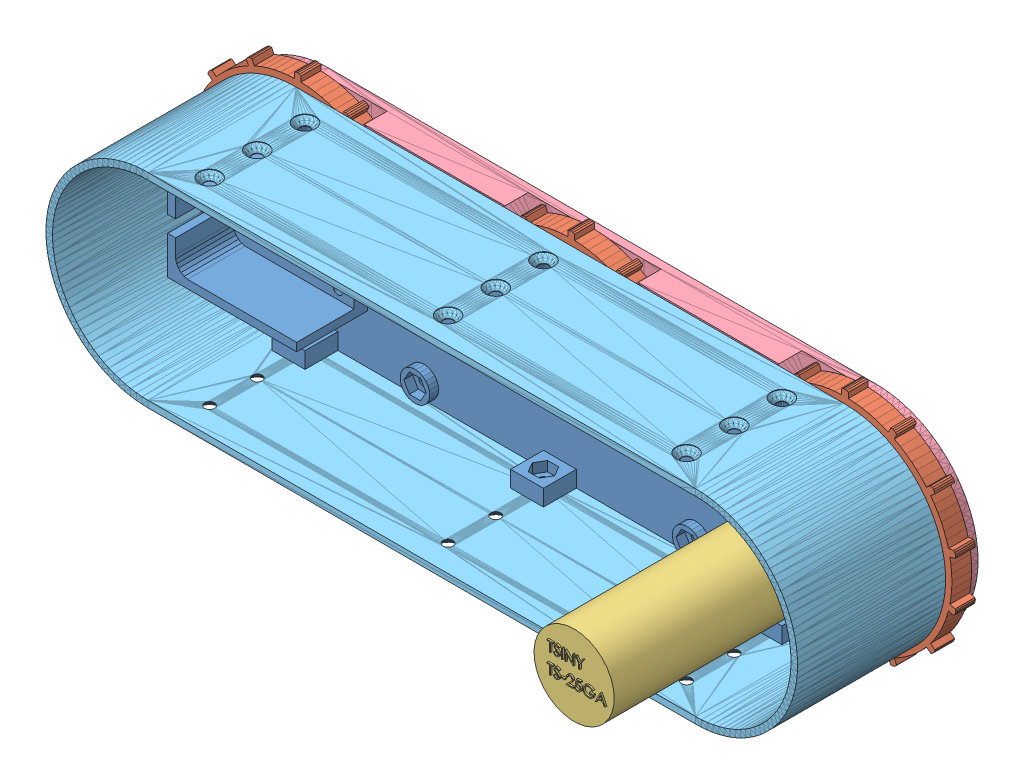
SolidWorks assembly Wheel Assembly with Cover, configuration Default. Lengths in mm.
Overall size (331.86 130.52 98.86).
8 component instances, 6 part files, 0 mates.
Components (placement in the parent):
- Motor_mount_plateV1-1: Motor_mount_plateV1 [Default] at (-100.9316 65.0429 10.2771) size (224.5 58 24.5)
- TrackWheel_V1-1: TrackWheel_V1 [Default] at (-184.1875 65.0685 3.7212) size (67.25 68.9 11)
- TrackWheel_V1-2: TrackWheel_V1 [Default] at (-100.9384 65.0603 3.8007) size (67.25 68.9 11)
- TrackWheel_V1-3: TrackWheel_V1 [Default] at (-17.733 65.0369 3.801) size (67.25 68.9 11)
- TSINY TS-25GA GearMotor with Encoder-2: TSINY TS-25GA GearMotor with Encoder [Default] at (-18.0287 65.0442 91.8595) x (-1 0 0) z (0 -1 0) size (24.4 82 24.4)
- Wheel_cover_14_t-1: Wheel_cover_14_t [Default] at (-100.937 65.0457 2.7818) x (-1 0 0) z (0 0 -1) size (228.17 62 9.5)
- Motor_cover-1: Motor_cover [Default] at (-100.9338 65.0785 10.2768) size (228.5 62 45)
- MotorBrace^Wheel Assembly with Cover-1: MotorBrace^Wheel Assembly with Cover [Default] at (-52.7522 76.7462 108.3111) x (1 0 0) z (0 0 -1) size (32.6 48 10.25)
